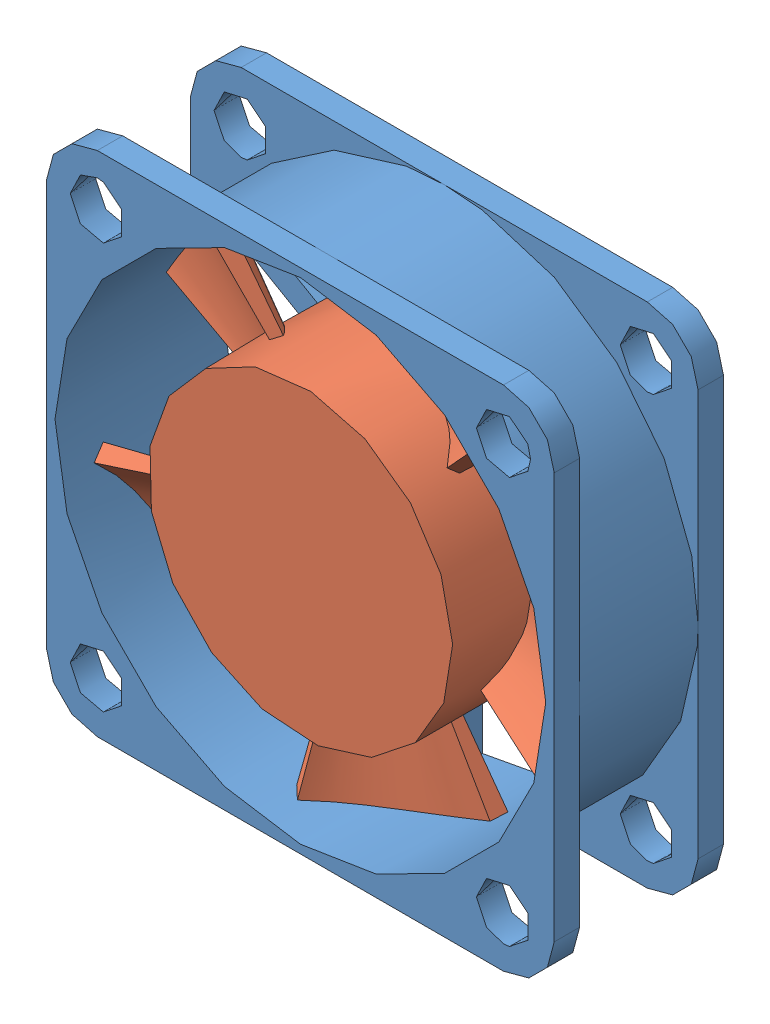
SolidWorks assembly KDE0503PFB3, configuration KDE0503PFB3. Lengths in mm.
Overall size (32.03 32.1 10).
2 component instances, 2 part files, 2 mates.
Components (placement in the parent):
- Fan_HouseKDE0503PFB3-1: Fan_HouseKDE0503PFB3 [KDE0503PFB3] at origin size (30 30 10)
- FanKDE0503PFB3-1: FanKDE0503PFB3 [KDE0503PFB3] x (0 0 -1) z (-0.159975 -0.987121 0) size (8.5 27.91 28)
Mates (geometry in assembly coordinates):
- Coincident1: coincident anti-aligned: plane of Fan_HouseKDE0503PFB3-1 through (0 0 0) normal (0 0 1); plane of FanKDE0503PFB3-1
- Coincident2: coincident aligned: axis of FanKDE0503PFB3-1 through (0 0 12.1385) axis (0 0 -1); axis of Fan_HouseKDE0503PFB3-1 through (0 0 10) axis (0 0 -1)
